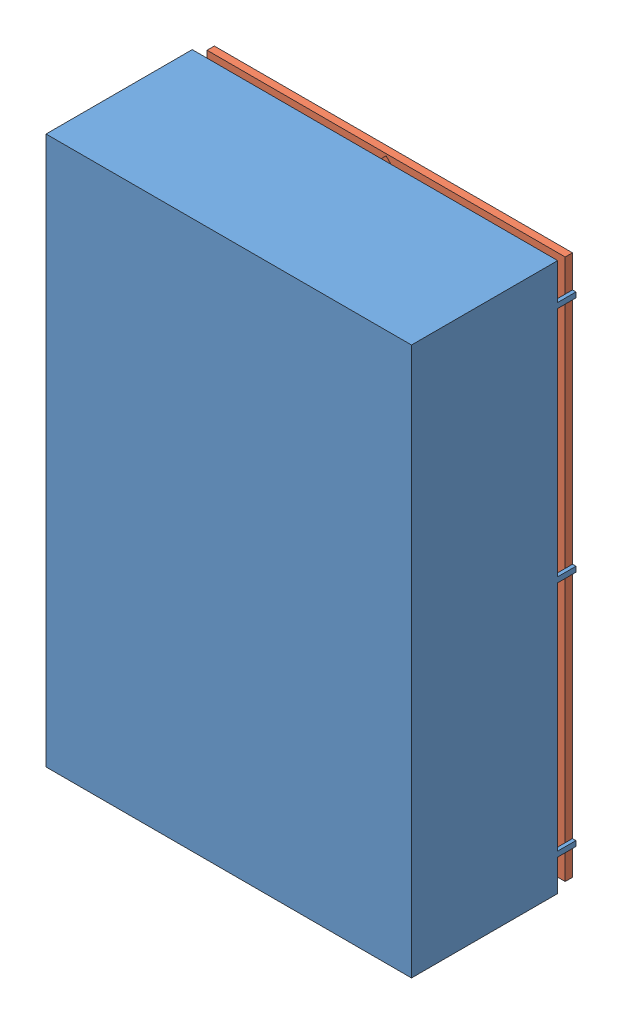
SolidWorks assembly SablierElectronique, configuration Défaut. Lengths in mm.
Overall size (200 300 90).
2 component instances, 2 part files, 4 mates.
Components (placement in the parent):
- PièceSablier2008-Box-1: PièceSablier2008-Box [Défaut] at origin size (200 300 90)
- PièceSablier2008-Top-1: PièceSablier2008-Top [Défaut] at (-32.8476 -252.3803 -10) size (196 296 7)
Mates (geometry in assembly coordinates):
- Parallèle3: parallel: line of PièceSablier2008-Box-1 through (141.474 29.3883 4.1) axis (0 -1 0); line of PièceSablier2008-Top-1 through (141.2849 29.0386 -4.9573) axis (0 -1 0)
- Parallèle1: parallel: line of PièceSablier2008-Box-1 through (196.2 -54.726 29.3883) axis (0 1 0); line of PièceSablier2008-Top-1 through (141.2849 29.0386 -8.9573) axis (-1 0 0)
- Parallèle2: parallel: line of PièceSablier2008-Box-1 through (196.2 -54.726 29.3883) axis (0 1 0); line of PièceSablier2008-Top-1 through (141.2849 29.0386 -8.9573) axis (-1 0 0)
- Coïncidente5: coincident aligned: line of PièceSablier2008-Box-1 through (141.474 8.5966 -10) axis (0 1 0); line of PièceSablier2008-Top-1 through (141.474 -266.9614 -10) axis (0 1 0)
